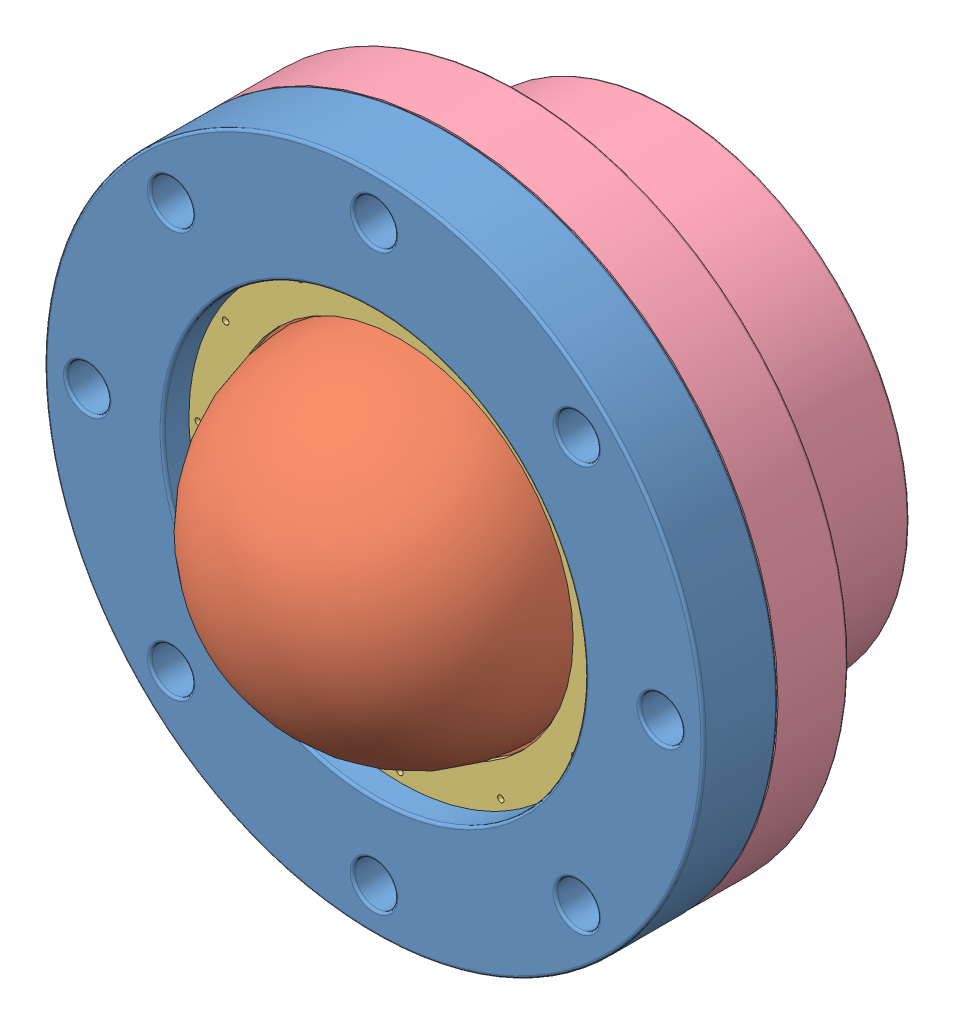
SolidWorks assembly NEW_7inEZTops_Dome_Assembly_2, configuration Default. Lengths in mm.
Overall size (349.97 349.97 221.95).
4 component instances, 4 part files, 6 mates.
Components (placement in the parent):
- 7inEZTops_8in PVC Flange Closed - Dome Mount 2-1: 7inEZTops_8in PVC Flange Closed - Dome Mount 2 [4881K973] at (126.9498 228.6178 238.3576) size (342.9 342.9 39.05)
- 7inEZTops_Custom Dome_v2-1: 7inEZTops_Custom Dome_v2 [Default] at (126.9498 228.6178 234.9788) x (0.893952 0.448162 0) z (0.448162 -0.893952 0) size (203.2 88.9 203.2)
- NEW_EZTops_clamp-ring-1: NEW_EZTops_clamp-ring [Default] at (126.9498 228.6178 242.9788) x (0.999999 -0.001561 0) z (0.001561 0.999999 0) size (220 3 220)
- 8in PVC Flange-1: 8in PVC Flange [4881K224] at (126.9498 228.6178 217.8153) x (-0.020828 0.999783 0) z (0 0 -1) size (342.9 342.9 115.89)
Mates (geometry in assembly coordinates):
- Concentric1: concentric aligned: circle of 7inEZTops_8in PVC Flange Closed - Dome Mount 2-1; circle of 7inEZTops_Custom Dome_v2-1
- Coincident2: coincident anti-aligned: plane of 7inEZTops_8in PVC Flange Closed - Dome Mount 2-1 through (126.9498 228.6178 234.9788) normal (0 0 1); plane of 7inEZTops_Custom Dome_v2-1 through (36.1242 183.0845 234.9788) normal (0 0 -1)
- Concentric2: concentric aligned: circle of 7inEZTops_Custom Dome_v2-1; circle of NEW_EZTops_clamp-ring-1
- Coincident3: coincident anti-aligned: plane of 7inEZTops_Custom Dome_v2-1 through (36.1242 183.0845 239.9788) normal (0 0 1); plane of NEW_EZTops_clamp-ring-1 through (126.9498 228.6178 239.9788) normal (0 0 -1)
- Concentric3: concentric aligned: circle of 7inEZTops_8in PVC Flange Closed - Dome Mount 2-1; circle of 8in PVC Flange-1
- Coincident4: coincident anti-aligned: plane of 7inEZTops_8in PVC Flange Closed - Dome Mount 2-1 through (126.9498 228.6178 217.8153) normal (0 0 -1); plane of 8in PVC Flange-1 through (126.9498 228.6178 217.8153) normal (0 0 1)
